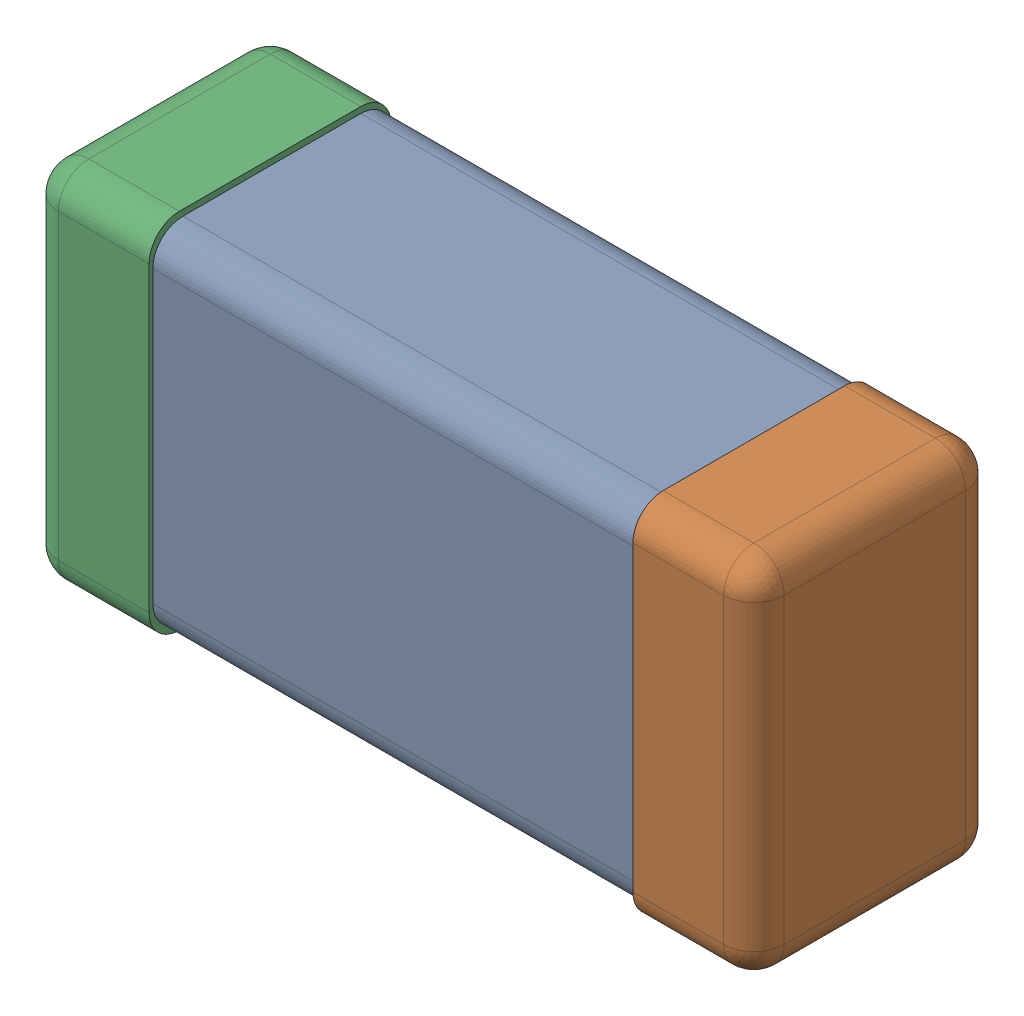
SolidWorks assembly C0201_020_1, configuration Standard. Lengths in mm.
Overall size (0.6 0.3 0.2).
3 component instances, 3 part files, 0 mates.
Components (placement in the parent):
- Part 3_2-1: Part 3_2 [Standard] at (0 0 -7.3015) size (0.5 0.29 0.2)
- Part 2_2-1: Part 2_2 [Standard] at (0 0 -7.3) size (0.1 0.3 0.2)
- Part 1_2-1: Part 1_2 [Standard] at (0 0 -7.3) size (0.1 0.3 0.2)
